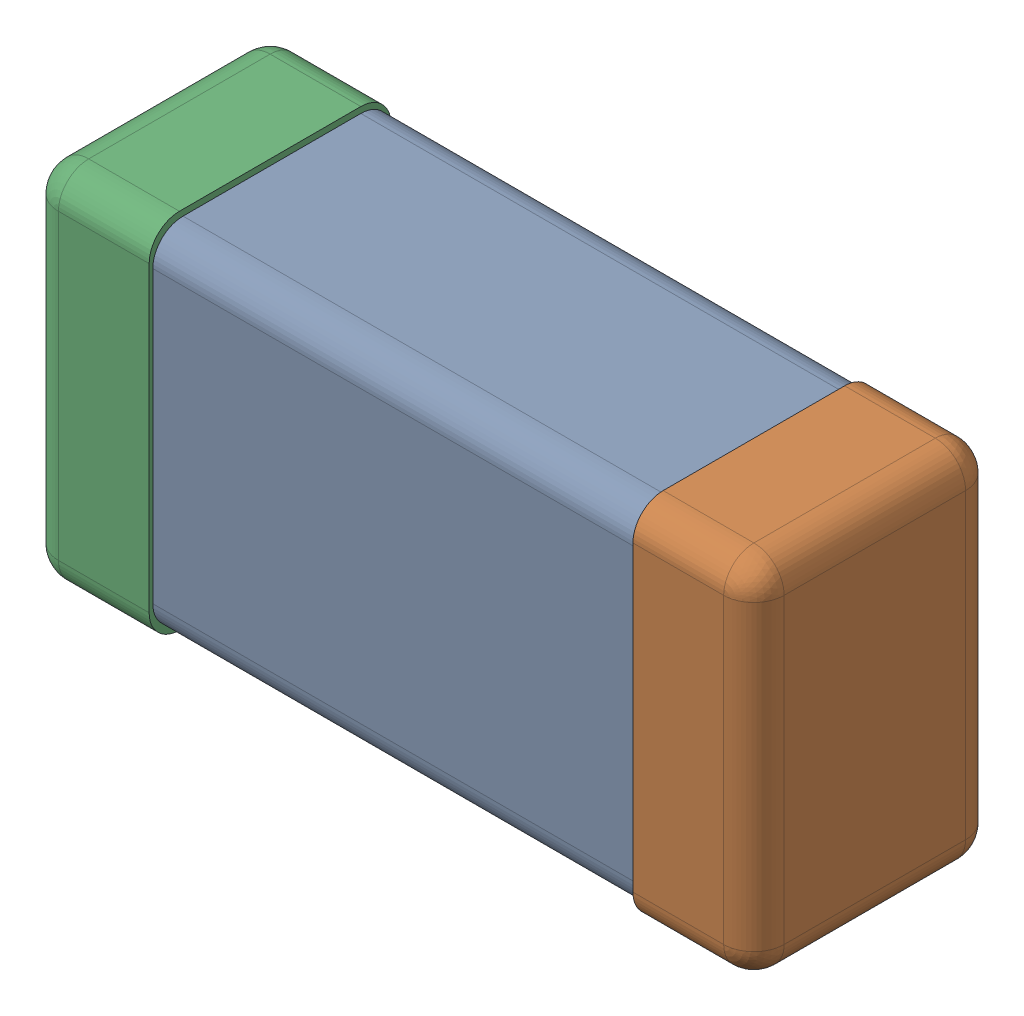
SolidWorks assembly C0201_020_29, configuration Standard. Lengths in mm.
Overall size (0.6 0.3 0.2).
3 component instances, 3 part files, 0 mates.
Components (placement in the parent):
- Part 3_2-1: Part 3_2 [Standard] at (0 0 -7.3015) size (0.5 0.29 0.2)
- Part 2_2-1: Part 2_2 [Standard] at (0 0 -7.3) size (0.1 0.3 0.2)
- Part 1_2-1: Part 1_2 [Standard] at (0 0 -7.3) size (0.1 0.3 0.2)
